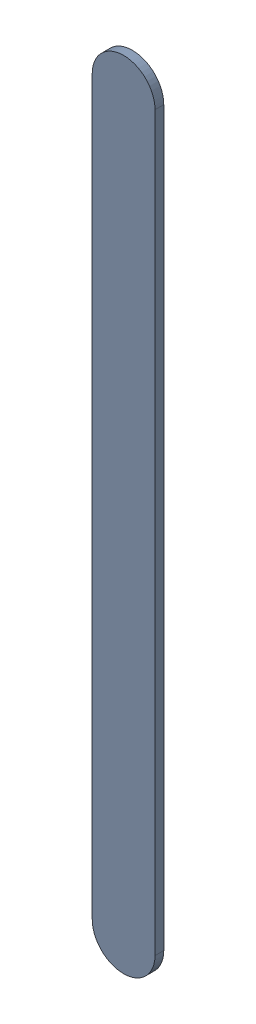
SolidWorks assembly Track (23.725mm,28.425mm)(23.725mm,31.391mm) on Top Layer, configuration Predeterminado. Lengths in mm.
Overall size (0.25 3.22 0.04).
2 component instances, 1 part files, 0 mates.
Components (placement in the parent):
- Track (23.725mm,28.425mm)(23.725mm,31.391mm) on Top Layer-1-1: Track (23.725mm,28.425mm)(23.725mm,31.391mm) on Top Layer-1 [Predeterminado] at (-68.317 -44.187 -0.0457) size (0.25 3.22 0.04)
  - Track (23.725mm,28.425mm)(23.725mm,31.391mm) on Top Layer-Part-1-1: Track (23.725mm,28.425mm)(23.725mm,31.391mm) on Top Layer-Part-1 [Predeterminado] at origin size (0.25 3.22 0.04)
